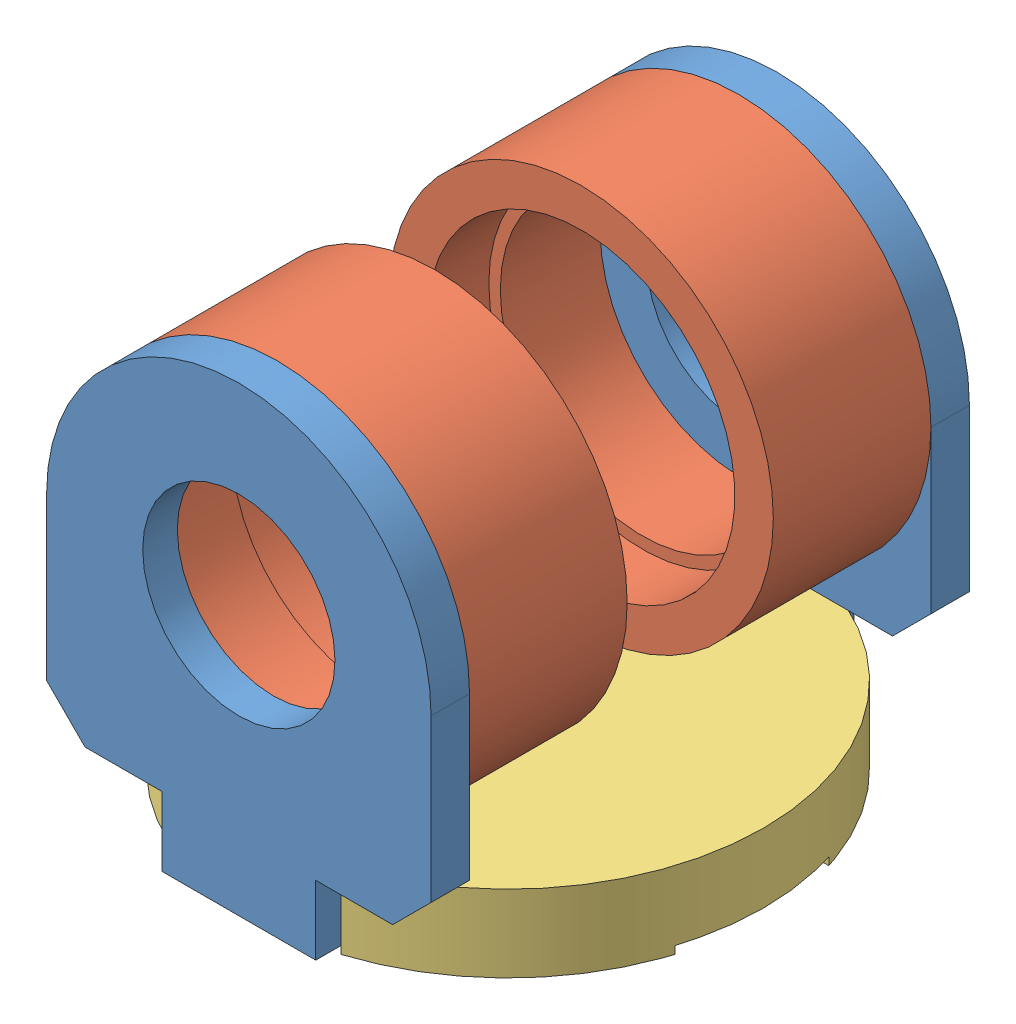
SolidWorks assembly 110303047-03, configuration 預設. Lengths in mm.
Overall size (133 122 140).
5 component instances, 3 part files, 8 mates.
Components (placement in the parent):
- 110303047-06-1: 110303047-06 [預設] at (30.561 -5.047 70.3169) size (100 120 10)
- 110303047-07-1: 110303047-07 [預設] at (30.561 -5.047 121.3169) x (1 0 0) z (0 -1 0) size (100 42 100)
- 110303047-05-1: 110303047-05 [預設] at (30.561 -77.047 140.3169) x (0 0 -1) z (0 1 0) size (126.84 133 20)
- 110303047-06-2: 110303047-06 [預設] at (30.561 -5.047 210.3169) x (-1 0 0) z (0 0 -1) size (100 120 10)
- 110303047-07-2: 110303047-07 [預設] at (30.561 -5.047 159.3169) x (1 0 0) z (0 1 0) size (100 42 100)
Mates (geometry in assembly coordinates):
- 輪廓中心1: profile center aligned: plane of 110303047-06-1 through (-2.8653 10.1592 124) normal (0 0 1); circle of 110303047-07-1
- 重合/共線/共點1: coincident anti-aligned: plane of 110303047-06-1 through (30.561 -5.047 80.3169) normal (0 0 1); plane of 110303047-05-1 through (10.561 -57.047 80.3169) normal (0 0 -1)
- 重合/共線/共點2: coincident anti-aligned: plane of 110303047-06-1 through (10.561 -5.047 80.3169) normal (-1 0 0); plane of 110303047-05-1 through (10.561 -57.047 76.8957) normal (1 0 0)
- 重合/共線/共點3: coincident anti-aligned: plane of 110303047-06-1 through (30.561 -57.047 80.3169) normal (0 -1 0); plane of 110303047-05-1 through (30.561 -57.047 140.3169) normal (0 1 0)
- 輪廓中心2: profile center: circle of 110303047-07-2; plane of 110303047-06-2 through (30.561 -5.047 201.3169) normal (0 0 -1)
- 重合/共線/共點5: coincident anti-aligned: plane of 110303047-05-1 through (10.561 -57.047 200.3169) normal (0 0 1); plane of 110303047-06-2 through (30.561 -5.047 200.3169) normal (0 0 -1)
- 重合/共線/共點6: coincident anti-aligned: plane of 110303047-05-1 through (10.561 -57.047 203.7382) normal (1 0 0); plane of 110303047-06-2 through (10.561 -5.047 200.3169) normal (-1 0 0)
- 重合/共線/共點7: coincident anti-aligned: plane of 110303047-05-1 through (30.561 -57.047 140.3169) normal (0 1 0); plane of 110303047-06-2 through (30.561 -57.047 200.3169) normal (0 -1 0)
